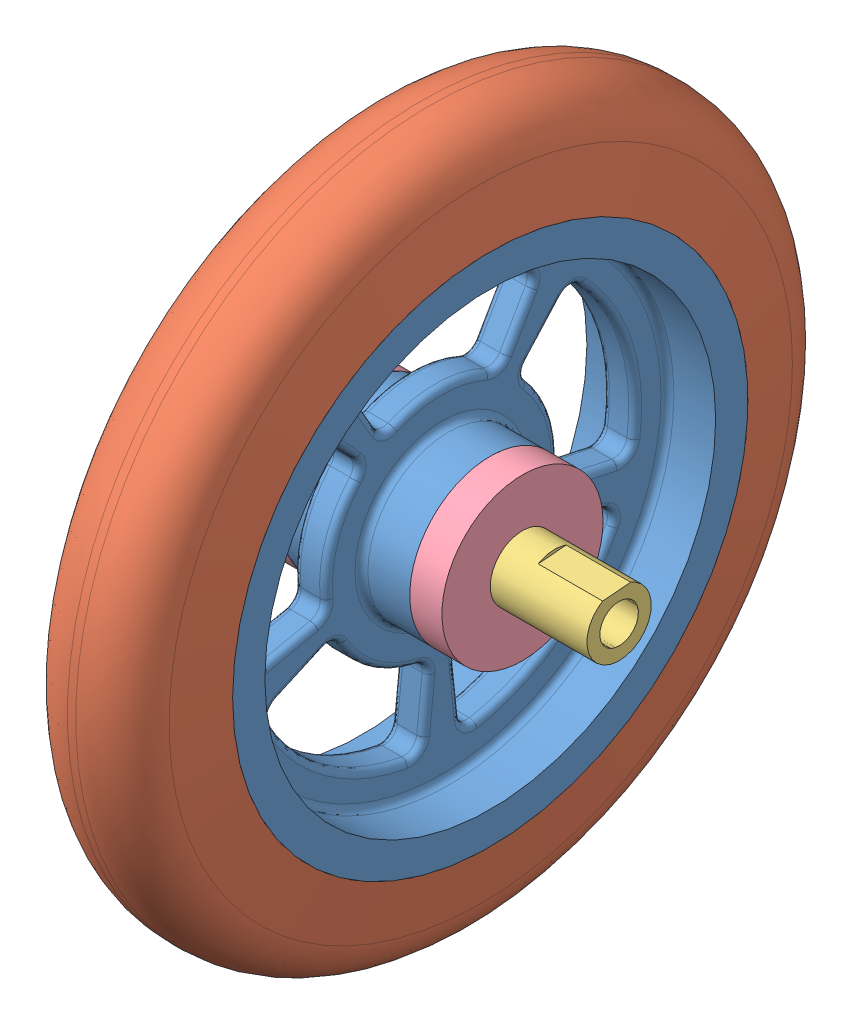
SolidWorks assembly Wheel and Axle, configuration Default. Lengths in mm.
Overall size (60 110 110).
5 component instances, 4 part files, 7 mates.
Components (placement in the parent):
- Wheel.-1: Wheel. [Default] at (27.5826 43.0888 61.6989) size (20 80 80)
- Tire.-1: Tire. [Default] at (27.5826 43.0888 61.6989) size (20 110 110)
- Axle.SLDPART-1: Axle.SLDPART [Default] at (27.5826 43.0888 61.6989) x (0 -0.083982 0.996467) z (-1 0 0) size (10 10 60)
- Washer-1: Washer [Default] at (17.5826 43.0888 61.6989) x (0 0 1) z (-1 0 0) size (25 25 5)
- Washer-2: Washer [Default] at (37.5826 43.0888 61.6989) x (0 -0.06397 -0.997952) z (1 0 0) size (25 25 5)
Mates (geometry in assembly coordinates):
- Coincident1: coincident aligned: circle of Wheel.-1; circle of Tire.-1
- Concentric1: concentric anti-aligned: cylinder of Wheel.-1 through (27.5826 43.0888 61.6989) axis (-1 0 0) radius 5; cylinder of Axle.SLDPART-1 through (-2.4174 43.0888 61.6989) axis (1 0 0) radius 5
- Coincident2: coincident anti-aligned: plane of Wheel.-1 through (27.5826 43.0888 61.6989) normal (1 0 0); plane of Axle.SLDPART-1 through (27.5826 43.0888 61.6989) normal (-1 0 0)
- Concentric3: concentric anti-aligned: cylinder of Axle.SLDPART-1 through (-2.4174 43.0888 61.6989) axis (1 0 0) radius 5; cylinder of Washer-2 through (42.5826 43.0888 61.6989) axis (-1 0 0) radius 5
- Coincident3: coincident anti-aligned: plane of Wheel.-1 through (37.5826 48.0888 61.6989) normal (1 0 0); plane of Washer-2 through (37.5826 43.0888 61.6989) normal (-1 0 0)
- Coincident4: coincident anti-aligned: cylinder of Axle.SLDPART-1 through (-2.4174 43.0888 61.6989) axis (1 0 0) radius 5; circle of Washer-1
- Coincident5: coincident anti-aligned: plane of Wheel.-1 through (17.5826 48.0888 61.6989) normal (-1 0 0); plane of Washer-1 through (17.5826 43.0888 61.6989) normal (1 0 0)
